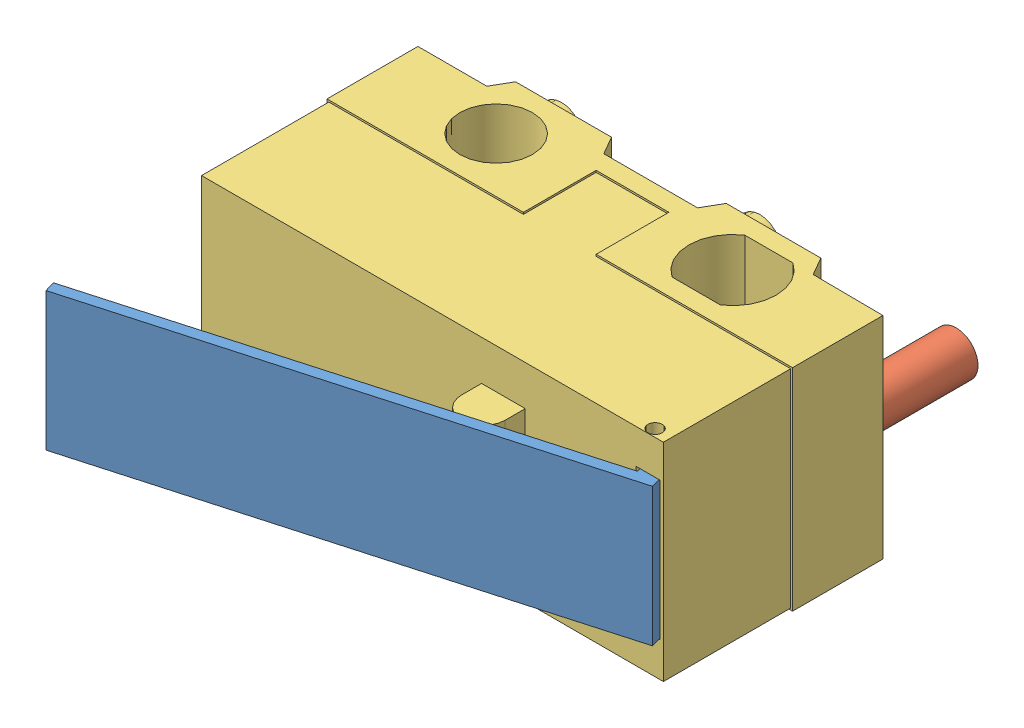
SolidWorks assembly KW10 Microswitch v2, configuration Predeterminado. Lengths in mm.
Overall size (13.18 5.8 12.93).
5 component instances, 3 part files, 0 mates.
Components (placement in the parent):
- Component2-1: Component2 [Predeterminado] at (-0.4015 5 5) x (-1 0 0) z (0 0 1) size (13.18 5.8 12.93)
  - Component3-1: Component3 [Predeterminado] at origin size (13.08 3.8 4.39)
    - Component6-1: Component6 [Predeterminado] at origin size (13.08 3.8 4.39)
  - Component7-1: Component7 [Predeterminado] at origin size (1.2 1.2 3)
  - Component8-1: Component8 [Predeterminado] at origin size (12.8 5.8 10.15)
